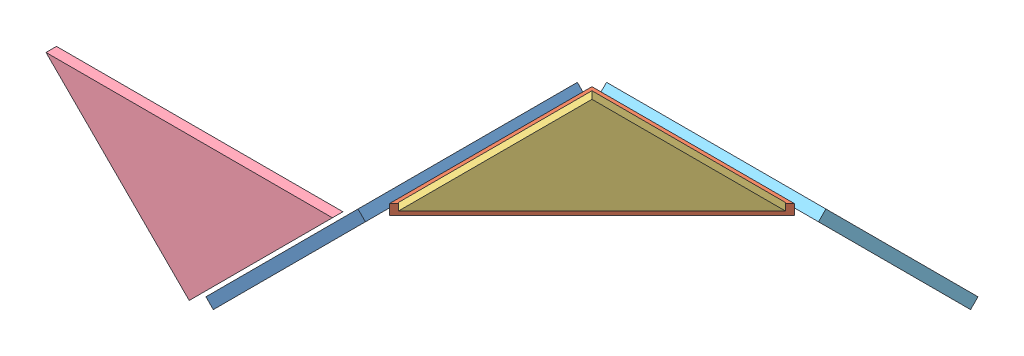
SolidWorks assembly Face Quarter, configuration Default. Lengths in mm.
Overall size (152.13 76.56 114.47).
12 component instances, 12 part files, 18 mates.
Components (placement in the parent):
- Goux Like-1: Goux Like [Default] at origin (suppressed, hidden)
- trapezoid-1: trapezoid [Default] at origin size (45.63 45.63 106.26)
- triangle 1-1: triangle 1 [Default] at origin size (57.93 3 57.93)
- triangle 2-1: triangle 2 [Default] at origin size (57.43 27.65 57.43)
- triangle 3-1: triangle 3 [Default] at origin size (81.93 40.97 3)
- triangle 4-1: triangle 4 [Default] at origin size (106.26 45.63 45.63)
- Joiner_1-1: Joiner_1 [Default] at (80.4015 -113.7049 80.4015) x (0 -1 0) z (-0.707107 0 0.707107) (suppressed, hidden)
- Joiner_2-1: Joiner_2 [Default] at (0 -160.803 0) x (-0.707107 -0.707107 0) z (0 0 1) (suppressed, hidden)
- Joiner_3-1: Joiner_3 [Default] at (80.4015 -80.4015 113.7049) x (0.707107 -0.707107 0) z (-0.707107 -0.707107 0) (suppressed, hidden)
- Joiner_Open - 1-2: Joiner_Open - 1 [Default] at (0 -113.7049 113.7049) x (0 1 0) z (1 0 0) (suppressed, hidden)
- Joiner_Open - 2-1: Joiner_Open - 2 [Default] at (47.0981 -113.7049 0) x (-1 0 0) z (0 0 1) (suppressed, hidden)
- Joiner_Open - 3-1: Joiner_Open - 3 [Default] at (53.601 -107.202 53.601) x (-0.816497 0.408248 0.408248) z (0.57735 0.57735 0.57735) (suppressed, hidden)
Mates (geometry in assembly coordinates):
- Coincident1: coincident anti-aligned: line of Goux Like-1 through (47.0981 -113.7049 113.7049) axis (0.707107 0 -0.707107); line of Joiner_1-1 through (143.3269 -113.7049 17.4761) axis (-0.707107 0 0.707107)
- Coincident2: coincident: plane of Joiner_1-1 through (80.4015 -113.7049 80.4015) normal (0.5 0.707107 0.5)
- Coincident3: coincident: plane of Joiner_1-1 through (80.4015 -113.7049 80.4015) normal (-0.707107 0 0.707107)
- Coincident4: coincident anti-aligned: line of Goux Like-1 through (0 -160.803 113.7049) axis (0 0 -1); line of Joiner_2-1 through (0 -160.803 -88.99) axis (0 0 1)
- Coincident6: coincident: plane of Joiner_2-1 through (0 -160.803 0) normal (1 0 0)
- Coincident9: coincident: plane of Joiner_2-1 through (0 -160.803 0) normal (0 0 1)
- Coincident10: coincident anti-aligned: line of Goux Like-1 through (47.0981 -113.7049 113.7049) axis (0.707107 0.707107 0); line of Joiner_3-1 through (143.3269 -17.4761 113.7049) axis (-0.707107 -0.707107 0)
- Coincident11: coincident: plane of Joiner_3-1 through (80.4015 -80.4015 113.7049) normal (-0.5 0.5 0.707107)
- Coincident12: coincident: plane of Joiner_3-1 through (80.4015 -80.4015 113.7049) normal (-0.707107 -0.707107 0)
- Coincident16: coincident: plane of Joiner_Open - 1-2 through (0 -113.7049 113.7049) normal (1 0 0)
- Coincident17: coincident anti-aligned: line of Goux Like-1 through (47.0981 -113.7049 113.7049) axis (-1 0 0); line of Joiner_Open - 1-2 through (-88.99 -113.7049 113.7049) axis (1 0 0)
- Coincident18: coincident: plane of Joiner_Open - 1-2 through (0 -113.7049 113.7049) normal (0 0.707107 0.707107)
- Coincident19: coincident anti-aligned: line of Joiner_Open - 2-1 through (47.0981 -113.7049 -88.99) axis (0 0 1); line of Goux Like-1 through (47.0981 -113.7049 113.7049) axis (0 0 -1)
- Coincident20: coincident: unknown of Joiner_Open - 2-1
- Parallel1: parallel aligned: plane of triangle 1-1 through (0 -115.2049 0) normal (0 -1 0); plane of Joiner_Open - 2-1 through (47.0981 -113.7049 0) normal (0 -1 0)
- Coincident22: coincident anti-aligned: line of Goux Like-1 through (47.0981 -113.7049 47.0981) axis (-0.57735 -0.57735 -0.57735); line of Joiner_Open - 3-1 through (2.2226 -158.5804 2.2226) axis (0.57735 0.57735 0.57735)
- Coincident23: coincident: plane of Joiner_Open - 3-1 through (53.601 -107.202 53.601) normal (-0.707107 0 0.707107)
- Coincident24: coincident: plane of Joiner_Open - 3-1 through (53.601 -107.202 53.601) normal (0.57735 0.57735 0.57735)
